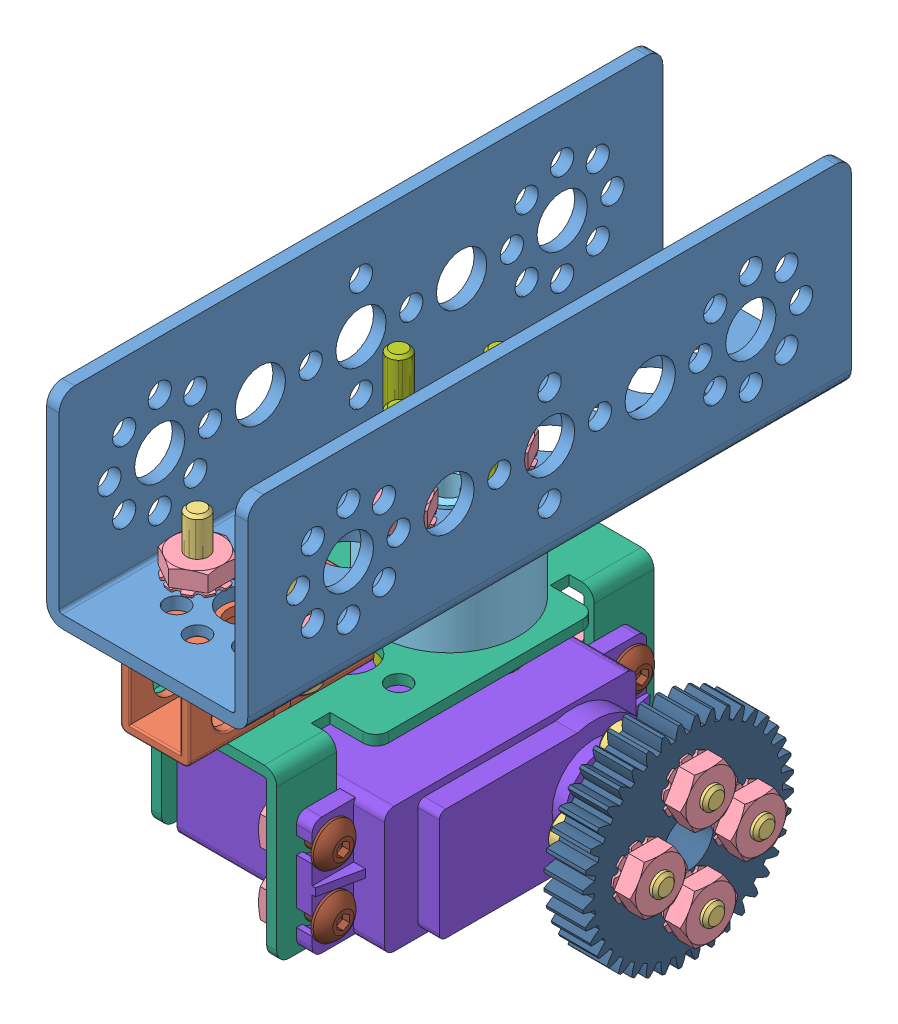
SolidWorks assembly Mantis step 12, configuration Default. Lengths in mm.
Overall size (59.63 78.07 96).
38 component instances, 12 part files, 25 mates.
Components (placement in the parent):
- Mantis step 10-1: Mantis step 10 [Default] at origin size (34.83 71.3 96)
  - Mantis step 9-1: Mantis step 9 [Default] at origin size (32 42.5 96)
    - Channel 96mm-1: Channel 96mm [Default] at origin size (32 32 96)
    - LEGO HPC-1: LEGO HPC [Default] at (0 0 32) x (-1 0 0) z (0 0 1) size (24.2 11.25 29.5)
    - Screw SHCS 6-32 x 0.5-1: Screw SHCS 6-32 x 0.5 [PreviewCfg] at (8 -4.7052 32) x (0 1 0) z (0 0 1) size (16.21 5.74 5.74)
    - Screw SHCS 6-32 x 0.5-2: Screw SHCS 6-32 x 0.5 [PreviewCfg] at (-8 -4.7052 32) x (0 1 0) z (0 0 1) size (16.21 5.74 5.74)
    - Nut Hex 6-32 KEP lock-1: Nut Hex 6-32 KEP lock [90675A007] at (-8 4.1828 32) size (8.74 3.59 9.17)
    - Nut Hex 6-32 KEP lock-2: Nut Hex 6-32 KEP lock [90675A007] at (8 4.1828 32) size (8.74 3.59 9.17)
  - Hub spacer-1: Hub spacer [Default] x (-1 0 0) z (0 1 0) size (22.2 22.2 17.7)
  - Bracket servo single-1: Bracket servo single [Default] at (0 -12.7 8) x (0 0 1) z (1 0 0) size (60 26.6 32.67)
  - Screw SHCS 6-32 x 1.250-1: Screw SHCS 6-32 x 1.250 [PreviewCfg] at (-8 -17.8052 0) x (0 1 0) z (0 0 -1) size (35.26 5.74 5.74)
  - Nut Hex 6-32 KEP lock-1: Nut Hex 6-32 KEP lock [90675A007] at (-8 4.1828 0) size (8.74 3.59 9.17)
  - Nut Hex 6-32 KEP lock-5: Nut Hex 6-32 KEP lock [90675A007] at (0 4.1828 -8) x (0 0 1) z (-1 0 0) size (8.74 3.59 9.17)
  - Nut Hex 6-32 KEP lock-6: Nut Hex 6-32 KEP lock [90675A007] at (8 4.1828 0) x (-1 0 0) z (0 0 -1) size (8.74 3.59 9.17)
  - Nut Hex 6-32 KEP lock-7: Nut Hex 6-32 KEP lock [90675A007] at (0 4.1828 8) x (0 0 -1) z (1 0 0) size (8.74 3.59 9.17)
  - Screw SHCS 6-32 x 1.250-5: Screw SHCS 6-32 x 1.250 [PreviewCfg] at (0 -17.8052 -8) x (0 1 0) z (1 0 0) size (35.26 5.74 5.74)
  - Screw SHCS 6-32 x 1.250-6: Screw SHCS 6-32 x 1.250 [PreviewCfg] at (8 -17.8052 0) x (0 1 0) z (0 0 1) size (35.26 5.74 5.74)
  - Screw SHCS 6-32 x 1.250-7: Screw SHCS 6-32 x 1.250 [PreviewCfg] at (0 -17.8052 8) x (0 1 0) z (-1 0 0) size (35.26 5.74 5.74)
- Servo motor HS475-1: Servo motor HS475 [Default] at (10.6 -29.3 -1.75) x (0 1 0) z (0 0 -1) size (20 43.2 56.6)
- Servo metal horn-1: Servo metal horn [Default] at (28.1 -29.3 -1.75) x (0 1 0) z (0 0 -1) size (22.2 6.2 22.2)
- Gear Metric 40T-1: Gear Metric 40T [PreviewCfg] at (36.3 -29.3 -1.75) x (-1 0 0) z (0 0 -1) size (6.2 33.53 33.53)
- Screw BHCS 6-32 x 0.375-1: Screw BHCS 6-32 x 0.375 [PreviewCfg] at (14.9542 -34.3 -15.75) x (-1 0 0) z (0 0 1) size (11.38 6.65 6.65)
- Nut Hex 6-32 KEP lock-1: Nut Hex 6-32 KEP lock [90675A007] at (6.8172 -34.3 -15.75) x (0 0 -1) z (0 1 0) size (8.74 3.59 9.17)
- Pan Cross Head_AI-1: Pan Cross Head_AI [CR-PHMS 0.112-40x0.375x0.375-N] at (32.132 -29.3 -1.75) x (-1 0 0) z (0 0 1) size (11.52 5.56 5.56)
- Screw SHCS 6-32 x 0.5-1: Screw SHCS 6-32 x 0.5 [PreviewCfg] at (24.5948 -37.3 -1.75) x (1 0 0) z (0 -1 0) size (16.21 5.74 5.74)
- Nut Hex 6-32 KEP lock-6: Nut Hex 6-32 KEP lock [90675A007] at (38.4828 -37.3 -1.75) x (0 -1 0) z (0 0 1) size (8.74 3.59 9.17)
- Nut Hex 6-32 KEP lock-9: Nut Hex 6-32 KEP lock [90675A007] at (6.8172 -34.3 31.75) x (0 0 -1) z (0 1 0) size (8.74 3.59 9.17)
- Nut Hex 6-32 KEP lock-10: Nut Hex 6-32 KEP lock [90675A007] at (6.8172 -24.3 31.75) x (0 0 -1) z (0 1 0) size (8.74 3.59 9.17)
- Nut Hex 6-32 KEP lock-11: Nut Hex 6-32 KEP lock [90675A007] at (6.8172 -24.3 -15.75) x (0 0 -1) z (0 1 0) size (8.74 3.59 9.17)
- Screw BHCS 6-32 x 0.375-5: Screw BHCS 6-32 x 0.375 [PreviewCfg] at (14.9542 -34.3 31.75) x (-1 0 0) z (0 0 1) size (11.38 6.65 6.65)
- Screw BHCS 6-32 x 0.375-6: Screw BHCS 6-32 x 0.375 [PreviewCfg] at (14.9542 -24.3 31.75) x (-1 0 0) z (0 0 1) size (11.38 6.65 6.65)
- Screw BHCS 6-32 x 0.375-7: Screw BHCS 6-32 x 0.375 [PreviewCfg] at (14.9542 -24.3 -15.75) x (-1 0 0) z (0 0 1) size (11.38 6.65 6.65)
- Nut Hex 6-32 KEP lock-12: Nut Hex 6-32 KEP lock [90675A007] at (38.4828 -29.3 -9.75) x (0 -1 0) z (0 0 1) size (8.74 3.59 9.17)
- Nut Hex 6-32 KEP lock-13: Nut Hex 6-32 KEP lock [90675A007] at (38.4828 -21.3 -1.75) x (0 -1 0) z (0 0 1) size (8.74 3.59 9.17)
- Nut Hex 6-32 KEP lock-14: Nut Hex 6-32 KEP lock [90675A007] at (38.4828 -29.3 6.25) x (0 -1 0) z (0 0 1) size (8.74 3.59 9.17)
- Screw SHCS 6-32 x 0.5-5: Screw SHCS 6-32 x 0.5 [PreviewCfg] at (24.5948 -29.3 -9.75) x (1 0 0) z (0 -1 0) size (16.21 5.74 5.74)
- Screw SHCS 6-32 x 0.5-6: Screw SHCS 6-32 x 0.5 [PreviewCfg] at (24.5948 -21.3 -1.75) x (1 0 0) z (0 -1 0) size (16.21 5.74 5.74)
- Screw SHCS 6-32 x 0.5-7: Screw SHCS 6-32 x 0.5 [PreviewCfg] at (24.5948 -29.3 6.25) x (1 0 0) z (0 -1 0) size (16.21 5.74 5.74)
Mates (geometry in assembly coordinates):
- MotorLock: parallel aligned: plane of Servo metal horn-1; plane of assembly through (0 0 0) normal (0 1 0)
- Concentric1: concentric anti-aligned: circle of Servo motor HS475-1; cylinder of Mantis step 10-1/Bracket servo single-1 through (10.6 -34.3 -15.75) axis (1 0 0) radius 1.85
- Concentric2: concentric anti-aligned: cylinder of Screw BHCS 6-32 x 0.375-1 through (14.9542 -34.3 -15.75) axis (1 0 0) radius 1.7526; cylinder of Servo motor HS475-1 through (13.1 -34.3 -15.75) axis (-1 0 0) radius 2.15
- Coincident2: coincident anti-aligned: plane of Servo motor HS475-1 through (13.1 -37.175 -16.85) normal (1 0 0); plane of Screw BHCS 6-32 x 0.375-1 through (13.1 -36.0526 -15.75) normal (-1 0 0)
- Concentric14: concentric anti-aligned: cylinder of Screw BHCS 6-32 x 0.375-1 through (14.9542 -34.3 -15.75) axis (1 0 0) radius 1.7526; circle of Nut Hex 6-32 KEP lock-1
- Coincident10: coincident aligned: plane of Mantis step 10-1/Bracket servo single-1 through (9 -39.3 -22) normal (-1 0 0); circle of Nut Hex 6-32 KEP lock-1
- Concentric6: concentric anti-aligned: cylinder of Servo motor HS475-1 through (27.2 -29.3 -1.75) axis (1 0 0) radius 1.5; cylinder of Servo metal horn-1 through (26.9 -29.3 -1.75) axis (-1 0 0) radius 2.85
- Coincident27: coincident anti-aligned: plane of Servo motor HS475-1 through (23.9 -29.3 -1.75) normal (1 0 0); plane of Servo metal horn-1 through (23.9 -29.3 -1.75) normal (-1 0 0)
- Concentric7: concentric anti-aligned: cylinder of Servo metal horn-1 through (30.1 -29.3 -1.75) axis (-1 0 0) radius 1.75; cylinder of Gear Metric 40T-1 through (-13.7001 -29.3 -1.75) axis (1 0 0) radius 4
- Concentric10: concentric anti-aligned: cylinder of Screw SHCS 6-32 x 0.5-1 through (-7.1552 -37.3 -1.75) axis (-1 0 0) radius 1.7526; circle of Servo metal horn-1
- Concentric13: concentric aligned: cylinder of Servo motor HS475-1 through (27.2 -29.3 -1.75) axis (1 0 0) radius 1.5; cylinder of Pan Cross Head_AI-1 through (57.532 -29.3 -1.75) axis (1 0 0) radius 1.4224
- Coincident18: coincident anti-aligned: plane of Servo metal horn-1 through (30.1 -29.3 -1.75) normal (1 0 0); plane of Gear Metric 40T-1 through (30.1 -29.3 -1.75) normal (-1 0 0)
- Coincident19: coincident anti-aligned: plane of Servo metal horn-1 through (28.1 -29.3 -1.75) normal (-1 0 0); plane of Screw SHCS 6-32 x 0.5-1 through (28.1 -37.3 1.1202) normal (1 0 0)
- Concentric15: concentric anti-aligned: cylinder of Screw SHCS 6-32 x 0.5-1 through (-7.1552 -37.3 -1.75) axis (-1 0 0) radius 1.7526; circle of Nut Hex 6-32 KEP lock-6
- Coincident23: coincident aligned: plane of Gear Metric 40T-1 through (36.3 -29.3 -1.75) normal (1 0 0); circle of Nut Hex 6-32 KEP lock-6
- Coincident28: coincident anti-aligned: plane of Mantis step 10-1/Bracket servo single-1 through (10.6 -14.3 -12.5) normal (1 0 0); plane of Servo motor HS475-1 through (10.6 -37.175 -16.85) normal (-1 0 0)
- Parallel2: unknown anti-aligned: unknown of Screw BHCS 6-32 x 0.375-1; unknown of Servo metal horn-1
- Parallel3: unknown aligned: plane of Nut Hex 6-32 KEP lock-1 through (6.8172 -34.3 -15.75) normal (0 1 0); unknown of Servo metal horn-1
- Coincident33: coincident anti-aligned: plane of Servo metal horn-1 through (30.1 -29.3 -1.75) normal (1 0 0); plane of Pan Cross Head_AI-1 through (30.1 -30.7224 -1.75) normal (-1 0 0)
- Parallel6: unknown anti-aligned: unknown of Pan Cross Head_AI-1; unknown of Servo metal horn-1
- Parallel7: unknown anti-aligned: plane of Screw SHCS 6-32 x 0.5-1 through (24.5948 -37.3 -1.75) normal (0 -1 0); unknown of Servo metal horn-1
- Parallel8: unknown anti-aligned: unknown of Nut Hex 6-32 KEP lock-6; unknown of Servo metal horn-1
- Parallel9: unknown aligned: unknown of Servo metal horn-1; unknown of Gear Metric 40T-1
- Parallel10: unknown aligned: unknown of Servo motor HS475-1; plane of assembly through (0 0 0) normal (0 1 0)
- HardwarePattern2: unknown: unknown of ?
